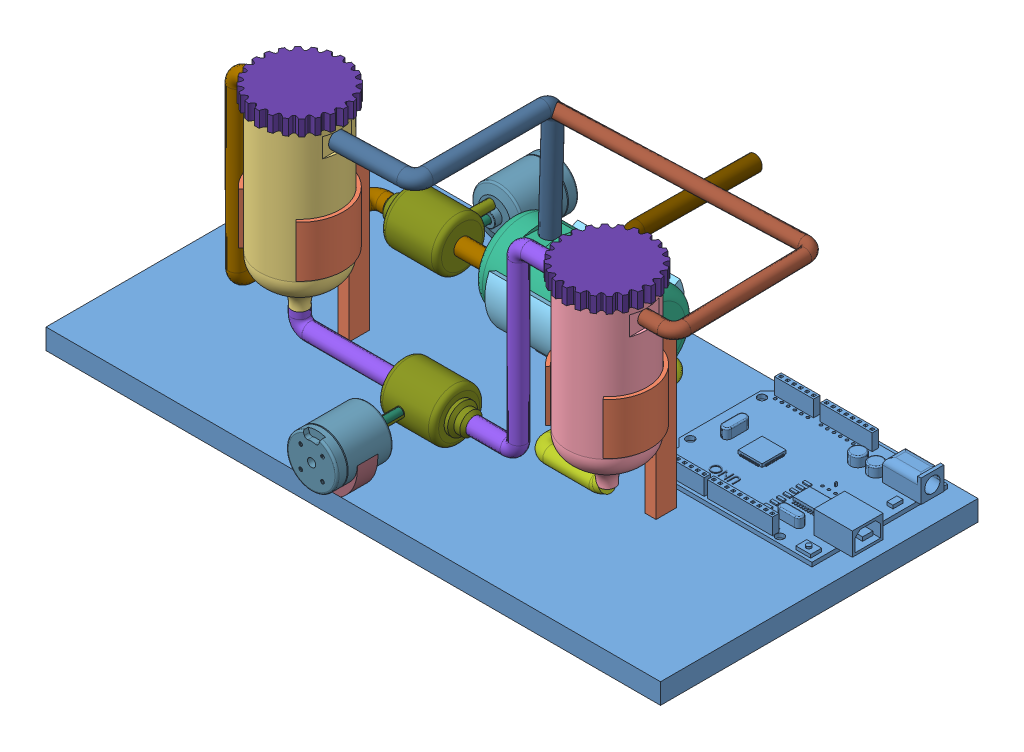
SolidWorks assembly Final_Assembly_2, configuration Default. Lengths in mm.
Overall size (60 25.78 37.41).
27 component instances, 21 part files, 66 mates.
Components (placement in the parent):
- Base_for_second_drawing-1: Base_for_second_drawing [Default] at (-81.5162 -11.5802 76.8948) size (60 2 31)
- Tank_Holder_for_2nd_drawing-1: Tank_Holder_for_2nd_drawing [Default] at (-65.9841 3.4198 98.6448) x (-1 0 0) z (0 -1 0) size (8.5 9.45 15)
- Tank_Holder_for_2nd_drawing-2: Tank_Holder_for_2nd_drawing [Default] at (-35.9841 3.4198 98.6448) x (-1 0 0) z (0 -1 0) size (8.5 9.45 15)
- Tank_number_1_2nd_drawing-1: Tank_number_1_2nd_drawing [Default] at (-65.9841 10.7017 98.6448) x (-0.000085 0 -1) z (1 0 -0.000085) size (7.98 17.32 7.98)
- Tank_number_2_2nd_drawing-1: Tank_number_2_2nd_drawing [Default] at (-35.9841 10.7017 98.6448) x (-0.008732 0 -0.999962) z (0.999962 0 -0.008732) size (7.98 17.32 7.98)
- Horizontal_Tank_Holder_Part_6-1: Horizontal_Tank_Holder_Part_6 [Default] at (-56.6325 -5.5802 85.1857) x (0 1 0) z (1 0 0) size (7.98 9.5 10)
- Horizontal_Tank_for_2nd_drawing-1: Horizontal_Tank_for_2nd_drawing [Default] at (-58.7066 -5.5802 85.1857) x (0 -0.053695 -0.998557) z (1 0 0) size (7.8 7.8 14)
- Part4^Final_Assembly_2-1: Part4^Final_Assembly_2 [Default] at (-44.7066 -5.5802 85.1857) x (0 -0.053695 -0.998557) z (1 0 0) size (14.98 2.22 9.06) (virtual)
- Part5^Final_Assembly_2-1: Part5^Final_Assembly_2 [Default] at (-65.9841 -6.6149 98.6448) x (0.000085 0 1) z (0 -1 0) size (1.64 26.91 19.06) (virtual)
- Part6^Final_Assembly_2-1: Part6^Final_Assembly_2 [Default] at (-58.7066 -5.5802 85.1857) x (0 0.053695 0.998557) z (-1 0 0) size (15.92 19.08 14.24) (virtual)
- Part7^Final_Assembly_2-1: Part7^Final_Assembly_2 [Default] at (-62.3736 10.7017 98.6445) x (-0.000085 0 -1) z (1 0 -0.000085) size (15.3 12.09 8.26) (virtual)
- Part8^Final_Assembly_2-1: Part8^Final_Assembly_2 [Default] at (-32.3845 10.7017 98.6133) x (-0.008732 0 -0.999962) z (0.999962 0 -0.008732) size (15.17 1.74 25.43) (virtual)
- IFM SM2000 2-1: IFM SM2000 2 [Default] at (-42.5097 -7.7102 -6.7742) x (1 0 0) z (0 -0.999971 0.007566) size (4.12 8 4.72)
- New_Battery_Holder-1: New_Battery_Holder [Default] at (-65.8928 -12.2169 76.8948) x (0 1 0) z (0 0 1) size (3.48 5.04 2)
- Maytech 5065 170kv-1: Maytech 5065 170kv [Default] at (-65.5966 -8.0145 48.1718) size (4.95 4.95 6.47)
- Motor_Shaft-1: Motor_Shaft [Default] at (-65.5965 -8.1019 79.7709) size (0.7 0.7 3)
- New_Battery_Holder-2: New_Battery_Holder [Default] at (-53.8928 -12.2169 105.8948) x (0 1 0) z (0 0 1) size (3.48 5.04 2)
- Maytech 5065 170kv-2: Maytech 5065 170kv [Default] at (-53.5965 -8.0145 135.9842) x (-1 0 0) z (0 0 -1) size (4.95 4.95 6.47)
- Motor_Shaft-2: Motor_Shaft [Default] at (-53.5965 -8.1019 101.2604) size (0.7 0.7 3)
- Motor_Pump_Connector-2: Motor_Pump_Connector [Default] at (-55.8992 -8.2619 98.6439) x (0.000085 -0.000001 1) z (0 1 0.000001) size (7.5 7.41 5)
- Tank_cap-1: Tank_cap [Default] at (-65.9841 12.2017 98.6448) x (-0.527643 0 -0.849466) z (0.849466 0 -0.527643) size (8.67 1.5 8.67)
- Tank_cap-2: Tank_cap [Default] at (-35.9841 12.2017 98.6448) x (0.84634 0 -0.532644) z (0.532644 0 0.84634) size (8.67 1.5 8.67)
- Part2^Final_Assembly_2-1: Part2^Final_Assembly_2 [Default] at (-58.7066 -2.0371 84.9952) x (0 -0.053695 -0.998557) z (0 0.998557 -0.053695) (virtual)
- Part3^Final_Assembly_2-1: Part3^Final_Assembly_2 [Default] at (-58.7066 -2.0371 84.9952) x (0 -0.053695 -0.998557) z (0 0.998557 -0.053695) (virtual)
- Part9^Final_Assembly_2-1: Part9^Final_Assembly_2 [Default] at (-58.7066 -2.0371 84.9952) x (0 -0.053695 -0.998557) z (0 0.998557 -0.053695) size (13.15 1.5 4.99) (virtual)
- arduino_UNO-2: arduino_UNO [Default] at (-2.255 -13.3904 110.9829) x (-1 0 0) z (0 0 -1) size (18.55 2.65 13.25)
- Motor_Pump_Connector-3: Motor_Pump_Connector [Default] at (-63.5204 -7.078 85.2663) x (0 0 -1) z (0 1 0) size (7.5 7.41 5)
Mates (geometry in assembly coordinates):
- Coincident3: coincident anti-aligned: plane of Base_for_second_drawing-1 through (-81.5162 -11.5802 76.8948) normal (0 1 0); plane of Tank_Holder_for_2nd_drawing-1 through (-65.9841 -11.5802 98.6448) normal (0 -1 0)
- Coincident4: coincident: point of assembly; point of Base_for_second_drawing-1; point of Tank_Holder_for_2nd_drawing-1
- Coincident5: coincident anti-aligned: plane of Base_for_second_drawing-1 through (-81.5162 -11.5802 76.8948) normal (0 1 0); plane of Tank_Holder_for_2nd_drawing-2 through (-35.9841 -11.5802 98.6448) normal (0 -1 0)
- Coincident7: coincident: point of assembly; point of Base_for_second_drawing-1; point of Tank_Holder_for_2nd_drawing-2
- Concentric4: concentric aligned: cylinder of Tank_Holder_for_2nd_drawing-1 through (-65.9841 -1.5802 98.6448) axis (0 1 0) radius 3.9; cylinder of Tank_number_1_2nd_drawing-1 through (-65.9841 10.7017 98.6448) axis (0 1 0) radius 3.8791
- Concentric5: concentric aligned: cylinder of Tank_Holder_for_2nd_drawing-2 through (-35.9841 -1.5802 98.6448) axis (0 1 0) radius 3.9; cylinder of Tank_number_2_2nd_drawing-1 through (-35.9841 10.7017 98.6448) axis (0 1 0) radius 3.8791
- Distance2: distance = 8 mm: point of Tank_number_1_2nd_drawing-1; point of Base_for_second_drawing-1
- Distance3: distance = 8 mm: point of Tank_number_2_2nd_drawing-1; point of Base_for_second_drawing-1
- Parallel1: parallel anti-aligned: line of Base_for_second_drawing-1 through (-81.5162 -11.5802 76.8948) axis (0 0 1); line of Tank_Holder_for_2nd_drawing-1 through (-66.5162 -11.5802 94.3948) axis (0 0 -1)
- Parallel2: parallel aligned: line of Base_for_second_drawing-1 through (-21.5162 -11.5802 76.8948) axis (0 0 1); line of Tank_Holder_for_2nd_drawing-2 through (-35.452 -11.5802 92.3948) axis (0 0 1)
- Coincident13: coincident: point of Base_for_second_drawing-1; point of Horizontal_Tank_Holder_Part_6-1
- Parallel3: parallel aligned: line of Base_for_second_drawing-1 through (-21.5162 -11.5802 76.8948) axis (0 0 1); line of Horizontal_Tank_Holder_Part_6-1 through (-47.4291 -11.5802 84.3948) axis (0 0 1)
- Parallel4: parallel anti-aligned: line of Base_for_second_drawing-1 through (-81.5162 -11.5802 76.8948) axis (0 0 1); line of Horizontal_Tank_Holder_Part_6-1 through (-55.6033 -11.5802 85.9771) axis (0 0 -1)
- Coincident16: coincident anti-aligned: plane of Base_for_second_drawing-1 through (-81.5162 -11.5802 76.8948) normal (0 1 0); plane of Horizontal_Tank_Holder_Part_6-1 through (-56.6325 -11.5802 85.1857) normal (0 -1 0)
- Concentric8: concentric aligned: cylinder of Horizontal_Tank_Holder_Part_6-1 through (-46.6325 -5.5802 85.1857) axis (-1 0 0) radius 4; cylinder of Horizontal_Tank_for_2nd_drawing-1 through (-44.7066 -5.5802 85.1857) axis (-1 0 0) radius 3.9
- Distance6: distance = 1.926 mm aligned: plane of Horizontal_Tank_for_2nd_drawing-1 through (-44.7066 -5.5802 85.1857) normal (1 0 0); plane of Horizontal_Tank_Holder_Part_6-1 through (-46.6325 -5.5802 85.1857) normal (1 0 0)
- InPlace1: in place: plane of ? through (-44.7066 -5.0802 85.1857) normal (1 0 0); plane of ? through (-44.7066 0 0) normal (1 0 0); moOrthogonalPlaneRef_w of ? through (-44.7066 -5.0802 85.1857) normal (1 0 0); plane of ? through (-44.7066 0 0) normal (0 1 0); plane of ? through (-44.7066 -5.0802 85.1857) normal (1 0 0); plane of ? through (-44.7066 0 0) normal (0 0 -1); plane of Horizontal_Tank_for_2nd_drawing-1 through (-44.7066 -5.5802 85.1857) normal (1 0 0); unknown of Part4^Final_Assembly_2-1
- Coincident20: coincident aligned: plane of Horizontal_Tank_for_2nd_drawing-1; plane of Part4^Final_Assembly_2-1
- Coincident21: coincident aligned: moOrthogonalPlaneRef_w of Horizontal_Tank_for_2nd_drawing-1; plane of Part4^Final_Assembly_2-1 through (-44.7066 -5.5802 85.1857) normal (0 0.998557 -0.053695)
- Coincident22: coincident anti-aligned: moOrthogonalPlaneRef_w of Horizontal_Tank_for_2nd_drawing-1; plane of Part4^Final_Assembly_2-1 through (-44.7066 -5.5802 85.1857) normal (0 -0.053695 -0.998557)
- InPlace2: in place: plane of Tank_number_1_2nd_drawing-1 through (-65.984 -6.6149 99.4448) normal (0 -1 0); plane of ? through (0 -6.6149 0) normal (0 -1 0); plane of Tank_number_1_2nd_drawing-1 through (-65.984 -6.6149 99.4448) normal (0 -1 0); plane of ? through (0 -6.6149 0) normal (0 0 -1); plane of Tank_number_1_2nd_drawing-1 through (-65.984 -6.6149 99.4448) normal (0 -1 0); plane of ? through (0 -6.6149 0) normal (-1 0 0); plane of Tank_number_1_2nd_drawing-1 through (-65.984 -6.6149 99.4448) normal (0 -1 0); unknown of Part5^Final_Assembly_2-1
- Coincident23: coincident aligned: plane of Tank_number_1_2nd_drawing-1; plane of Part5^Final_Assembly_2-1
- Coincident24: coincident aligned: moOrthogonalPlaneRef_w of Tank_number_1_2nd_drawing-1 through (-65.9841 -6.6149 98.6448) normal (-1 0 0.000085); plane of Part5^Final_Assembly_2-1 through (-65.9841 -6.6149 98.6448) normal (-1 0 0.000085)
- Coincident25: coincident anti-aligned: moOrthogonalPlaneRef_w of Tank_number_1_2nd_drawing-1 through (-65.9841 -6.6149 98.6448) normal (-0.000085 0 -1); plane of Part5^Final_Assembly_2-1 through (-65.9841 -6.6149 98.6448) normal (0.000085 0 1)
- InPlace3: in place: plane of ? through (-58.7066 -6.5802 85.1857) normal (-1 0 0); plane of ? through (-58.7066 0 0) normal (-1 0 0); plane of ? through (-58.7066 -6.5802 85.1857) normal (-1 0 0); plane of ? through (-58.7066 0 0) normal (0 1 0); plane of ? through (-58.7066 -6.5802 85.1857) normal (-1 0 0); plane of ? through (-58.7066 0 0) normal (0 0 1); plane of Horizontal_Tank_for_2nd_drawing-1 through (-58.7066 -5.5802 85.1857) normal (-1 0 0); unknown of Part6^Final_Assembly_2-1
- Coincident26: coincident aligned: plane of Horizontal_Tank_for_2nd_drawing-1; plane of Part6^Final_Assembly_2-1
- Coincident27: coincident aligned: moOrthogonalPlaneRef_w of Horizontal_Tank_for_2nd_drawing-1; plane of Part6^Final_Assembly_2-1 through (-58.7066 -5.5802 85.1857) normal (0 0.998557 -0.053695)
- Coincident28: coincident anti-aligned: moOrthogonalPlaneRef_w of Horizontal_Tank_for_2nd_drawing-1; plane of Part6^Final_Assembly_2-1 through (-58.7066 -5.5802 85.1857) normal (0 0.053695 0.998557)
- InPlace4: in place: plane of Tank_number_1_2nd_drawing-1 through (-62.374 10.162 93.6445) normal (1 0 -0.000085); plane of ? through (-62.3819 0 0.0053) normal (1 0 -0.000085); plane of Tank_number_1_2nd_drawing-1 through (-62.374 10.162 93.6445) normal (1 0 -0.000085); plane of ? through (-62.3819 0 0.0053) normal (0 1 0); plane of Tank_number_1_2nd_drawing-1 through (-62.374 10.162 93.6445) normal (1 0 -0.000085); plane of ? through (-62.3819 0 0.0053) normal (-0.000085 0 -1); plane of Tank_number_1_2nd_drawing-1 through (-62.374 10.162 93.6445) normal (1 0 -0.000085); unknown of Part7^Final_Assembly_2-1
- Coincident29: coincident aligned: plane of Tank_number_1_2nd_drawing-1; plane of Part7^Final_Assembly_2-1
- Coincident30: coincident aligned: moOrthogonalPlaneRef_w of Tank_number_1_2nd_drawing-1 through (-62.3736 10.7017 98.6445) normal (0 1 0); plane of Part7^Final_Assembly_2-1 through (-62.3736 10.7017 98.6445) normal (0 1 0)
- Coincident31: coincident anti-aligned: moOrthogonalPlaneRef_w of Tank_number_1_2nd_drawing-1 through (-62.3736 10.7017 98.6445) normal (0.000085 0 1); plane of Part7^Final_Assembly_2-1 through (-62.3736 10.7017 98.6445) normal (-0.000085 0 -1)
- InPlace5: in place: plane of Tank_number_2_2nd_drawing-1 through (-32.4282 8.2255 93.6135) normal (0.999962 0 -0.008732); plane of ? through (-33.2431 0 0.2903) normal (0.999962 0 -0.008732); plane of Tank_number_2_2nd_drawing-1 through (-32.4282 8.2255 93.6135) normal (0.999962 0 -0.008732); plane of ? through (-33.2431 0 0.2903) normal (0 1 0); plane of Tank_number_2_2nd_drawing-1 through (-32.4282 8.2255 93.6135) normal (0.999962 0 -0.008732); plane of ? through (-33.2431 0 0.2903) normal (-0.008732 0 -0.999962); plane of Tank_number_2_2nd_drawing-1 through (-32.4282 8.2255 93.6135) normal (0.999962 0 -0.008732); unknown of Part8^Final_Assembly_2-1
- Coincident32: coincident aligned: plane of Tank_number_2_2nd_drawing-1; plane of Part8^Final_Assembly_2-1
- Coincident33: coincident aligned: moOrthogonalPlaneRef_w of Tank_number_2_2nd_drawing-1 through (-32.3845 10.7017 98.6133) normal (0 1 0); plane of Part8^Final_Assembly_2-1 through (-32.3845 10.7017 98.6133) normal (0 1 0)
- Coincident34: coincident anti-aligned: moOrthogonalPlaneRef_w of Tank_number_2_2nd_drawing-1 through (-32.3845 10.7017 98.6133) normal (0.008732 0 0.999962); plane of Part8^Final_Assembly_2-1 through (-32.3845 10.7017 98.6133) normal (-0.008732 0 -0.999962)
- Concentric9: concentric anti-aligned: cylinder of Part4^Final_Assembly_2-1 through (-42.5096 -7.0704 86.2663) axis (0 0.007566 0.999971) radius 0.8; cylinder of IFM SM2000 2-1 through (-42.5096 -7.0085 94.4557) axis (0 -0.007566 -0.999971) radius 0.86
- Coincident18: coincident anti-aligned: plane of Base_for_second_drawing-1 through (-81.5162 -11.5802 76.8948) normal (0 1 0); plane of New_Battery_Holder-1 through (-66.5162 -11.5802 78.8948) normal (0 -1 0)
- Coincident19: coincident anti-aligned: line of Base_for_second_drawing-1 through (-21.5162 -11.5802 76.8948) axis (-1 0 0); line of New_Battery_Holder-1 through (-66.5162 -11.5802 76.8948) axis (1 0 0)
- Concentric10: concentric aligned: cylinder of New_Battery_Holder-1 through (-65.5965 -8.1019 78.8948) axis (0 0 -1) radius 2.4; cylinder of Maytech 5065 170kv-1 through (-65.5965 -8.1019 77.5493) axis (0 0 -1) radius 2.475
- Concentric11: concentric aligned: cylinder of Maytech 5065 170kv-1 through (-65.5965 -8.1019 80.7243) axis (0 0 -1) radius 0.4; cylinder of Motor_Shaft-1 through (-65.5965 -8.1019 82.7709) axis (0 0 -1) radius 0.35
- Coincident21: coincident anti-aligned: plane of Base_for_second_drawing-1 through (-81.5162 -11.5802 76.8948) normal (0 1 0); plane of New_Battery_Holder-2 through (-54.5162 -11.5802 107.8948) normal (0 -1 0)
- Coincident22: coincident aligned: line of Base_for_second_drawing-1 through (-81.5162 -11.5802 107.8948) axis (1 0 0); line of New_Battery_Holder-2 through (-54.5162 -11.5802 107.8948) axis (1 0 0)
- Concentric16: concentric anti-aligned: cylinder of New_Battery_Holder-2 through (-53.5965 -8.1019 107.8948) axis (0 0 -1) radius 2.4; cylinder of Maytech 5065 170kv-2 through (-53.5965 -8.1019 106.6068) axis (0 0 1) radius 2.475
- Concentric17: concentric anti-aligned: cylinder of Maytech 5065 170kv-2 through (-53.5965 -8.1019 103.4318) axis (0 0 1) radius 0.4; cylinder of Motor_Shaft-2 through (-53.5965 -8.1019 104.2604) axis (0 0 -1) radius 0.35
- Concentric19: concentric aligned: cylinder of Part5^Final_Assembly_2-1 through (-64.9841 -8.2619 98.6447) axis (1 0 -0.000085) radius 0.8; cylinder of Motor_Pump_Connector-2 through (-53.4875 -8.2619 98.6437) axis (1 0 -0.000085) radius 0.6841
- Concentric26: concentric anti-aligned: cylinder of Part6^Final_Assembly_2-1 through (-58.7066 -8.078 85.2663) axis (-1 0 0) radius 0.8; cylinder of Motor_Pump_Connector-1 through (-65.3451 -8.078 85.2663) axis (1 0 0) radius 0.6841
- Concentric27: concentric anti-aligned: circle of Tank_number_1_2nd_drawing-1; circle of Tank_cap-1
- Concentric28: concentric anti-aligned: circle of Tank_number_2_2nd_drawing-1; circle of Tank_cap-2
- Coincident25: coincident anti-aligned: plane of Tank_number_1_2nd_drawing-1 through (-65.9838 10.7017 102.5239) normal (0 1 0); plane of Tank_cap-1 through (-65.9841 10.7017 98.6448) normal (0 -1 0)
- Coincident26: coincident anti-aligned: plane of Tank_number_2_2nd_drawing-1 through (-35.9502 10.7017 102.5237) normal (0 1 0); plane of Tank_cap-2 through (-35.9841 10.7017 98.6448) normal (0 -1 0)
- InPlace6: in place: plane of ? through (-58.7066 -3.574 75.0096) normal (0 0.998557 -0.053695); plane of ? through (0 -7.5856 0.4079) normal (0 0.998557 -0.053695); plane of ? through (-58.7066 -3.574 75.0096) normal (0 0.998557 -0.053695); plane of ? through (0 -7.5856 0.4079) normal (0 -0.053695 -0.998557); plane of ? through (-58.7066 -3.574 75.0096) normal (0 0.998557 -0.053695); plane of ? through (0 -7.5856 0.4079) normal (1 0 0); plane of Horizontal_Tank_for_2nd_drawing-1 through (-58.7066 -2.574 75.0096) normal (0 0.998557 -0.053695); unknown of ?
- Coincident27: coincident aligned: plane of Horizontal_Tank_for_2nd_drawing-1; plane of Part2^Final_Assembly_2-1
- Coincident28: coincident aligned: moOrthogonalPlaneRef_w of Horizontal_Tank_for_2nd_drawing-1 through (-58.7066 -2.0371 84.9952) normal (-1 0 0); plane of Part2^Final_Assembly_2-1 through (-58.7066 -2.0371 84.9952) normal (-1 0 0)
- Coincident29: coincident anti-aligned: moOrthogonalPlaneRef_w of Horizontal_Tank_for_2nd_drawing-1 through (-58.7066 -2.0371 84.9952) normal (0 0.053695 0.998557); plane of Part2^Final_Assembly_2-1 through (-58.7066 -2.0371 84.9952) normal (0 -0.053695 -0.998557)
- InPlace7: in place: plane of ? through (-58.7066 -3.574 75.0096) normal (0 0.998557 -0.053695); plane of ? through (0 -7.5856 0.4079) normal (0 0.998557 -0.053695); plane of ? through (-58.7066 -3.574 75.0096) normal (0 0.998557 -0.053695); plane of ? through (0 -7.5856 0.4079) normal (0 -0.053695 -0.998557); plane of ? through (-58.7066 -3.574 75.0096) normal (0 0.998557 -0.053695); plane of ? through (0 -7.5856 0.4079) normal (1 0 0); plane of Horizontal_Tank_for_2nd_drawing-1 through (-58.7066 -2.574 75.0096) normal (0 0.998557 -0.053695); unknown of ?
- Coincident30: coincident aligned: plane of Horizontal_Tank_for_2nd_drawing-1; plane of Part3^Final_Assembly_2-1
- Coincident31: coincident aligned: moOrthogonalPlaneRef_w of Horizontal_Tank_for_2nd_drawing-1 through (-58.7066 -2.0371 84.9952) normal (-1 0 0); plane of Part3^Final_Assembly_2-1 through (-58.7066 -2.0371 84.9952) normal (-1 0 0)
- Coincident32: coincident anti-aligned: moOrthogonalPlaneRef_w of Horizontal_Tank_for_2nd_drawing-1 through (-58.7066 -2.0371 84.9952) normal (0 0.053695 0.998557); plane of Part3^Final_Assembly_2-1 through (-58.7066 -2.0371 84.9952) normal (0 -0.053695 -0.998557)
- InPlace8: in place: plane of ? through (-58.7066 -3.574 75.0096) normal (0 0.998557 -0.053695); plane of ? through (0 -7.5856 0.4079) normal (0 0.998557 -0.053695); plane of ? through (-58.7066 -3.574 75.0096) normal (0 0.998557 -0.053695); plane of ? through (0 -7.5856 0.4079) normal (0 -0.053695 -0.998557); plane of ? through (-58.7066 -3.574 75.0096) normal (0 0.998557 -0.053695); plane of ? through (0 -7.5856 0.4079) normal (1 0 0); plane of Horizontal_Tank_for_2nd_drawing-1 through (-58.7066 -2.574 75.0096) normal (0 0.998557 -0.053695); unknown of ?
- Coincident33: coincident aligned: plane of Horizontal_Tank_for_2nd_drawing-1; plane of Part9^Final_Assembly_2-1
- Coincident34: coincident aligned: moOrthogonalPlaneRef_w of Horizontal_Tank_for_2nd_drawing-1 through (-58.7066 -2.0371 84.9952) normal (-1 0 0); plane of Part9^Final_Assembly_2-1 through (-58.7066 -2.0371 84.9952) normal (-1 0 0)
- Coincident35: coincident anti-aligned: moOrthogonalPlaneRef_w of Horizontal_Tank_for_2nd_drawing-1 through (-58.7066 -2.0371 84.9952) normal (0 0.053695 0.998557); plane of Part9^Final_Assembly_2-1 through (-58.7066 -2.0371 84.9952) normal (0 -0.053695 -0.998557)
- Coincident27: coincident anti-aligned: plane of Base_for_second_drawing-1 through (-81.5162 -11.5802 76.8948) normal (0 1 0); plane of arduino_UNO-1 through (-51.9192 -11.5802 50.8794) normal (0 -1 0)
- Coincident28: coincident anti-aligned: plane of Base_for_second_drawing-1 through (-81.5162 -11.5802 76.8948) normal (0 1 0); plane of arduino_UNO-2 through (-23.8237 -11.5802 90.8033) normal (0 -1 0)
- Concentric29: concentric aligned: cylinder of Part6^Final_Assembly_2-1 through (-58.7066 -7.078 85.2663) axis (-1 0 0) radius 0.8; cylinder of Motor_Pump_Connector-3 through (-65.9321 -7.078 85.2663) axis (-1 0 0) radius 0.6841
